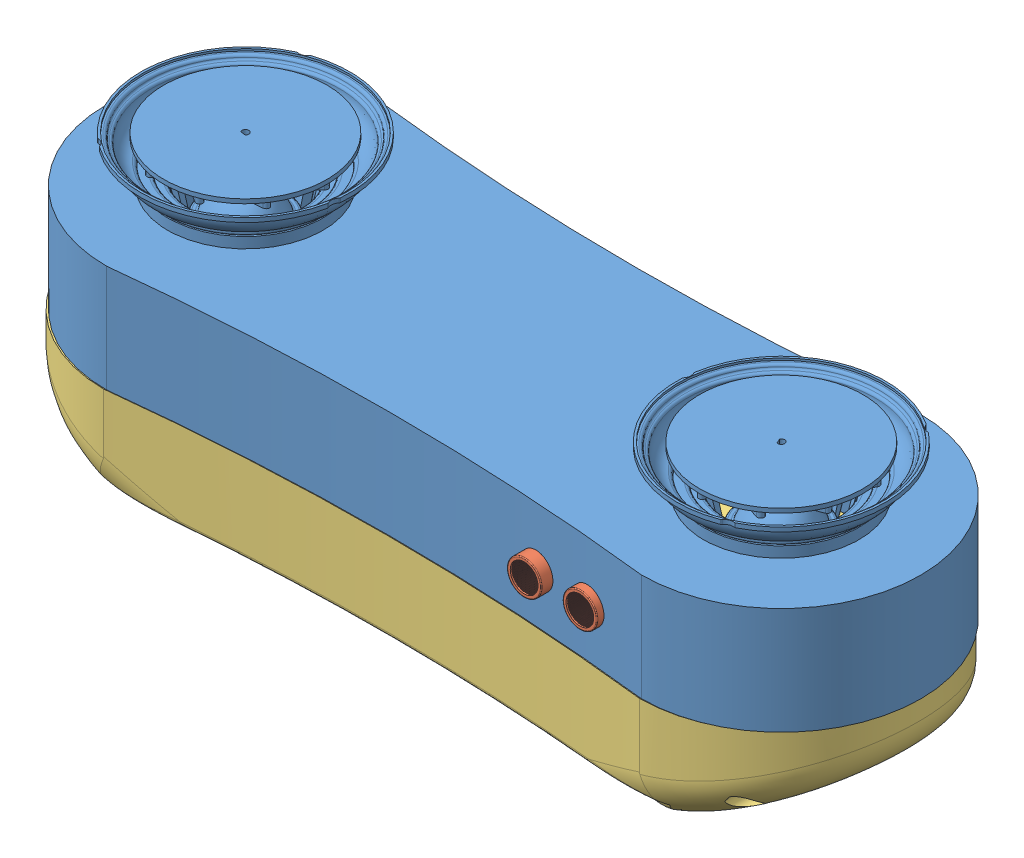
SolidWorks assembly Window_Cleaner, configuration Default. Lengths in mm.
Overall size (380.79 151.92 137.29).
3 component instances, 3 part files, 3 mates.
Components (placement in the parent):
- pembersih kaca-1: pembersih kaca [Default] at (-423.2674 131.0544 201.3212) size (380 100.9 130)
- Sensor Ultrasonic-2: Sensor Ultrasonic [Predeterminado] at (-174.2851 335.1756 527.8983) size (45.42 26.14 17.7)
- tutupcase-4: tutupcase [Default] at (-275.3933 497.9234 899.4636) x (1 0 0) z (0 0 -1) size (380 80.44 137.29)
Mates (geometry in assembly coordinates):
- Concentric1: concentric: cylinder of assembly; cylinder of pembersih kaca-1 through (-187.2851 335.1756 543.6924) axis (0 0 -1) radius 7.8; axis of Sensor Ultrasonic-2 through (-187.2851 335.1756 523.8717) axis (0 0 1)
- Coincident6: coincident anti-aligned: plane of pembersih kaca-1 through (-267.9497 312.491 473.6924) normal (0 -1 0); plane of tutupcase-4 through (-268.743 312.491 474.0245) normal (0 1 0)
- Concentric6: concentric aligned: cylinder of pembersih kaca-1 through (-161.2851 335.1756 543.6924) axis (0 0 -1) radius 7.8; cylinder of Sensor Ultrasonic-2 through (-161.2851 335.1756 539.8983) axis (0 0 -1) radius 8
